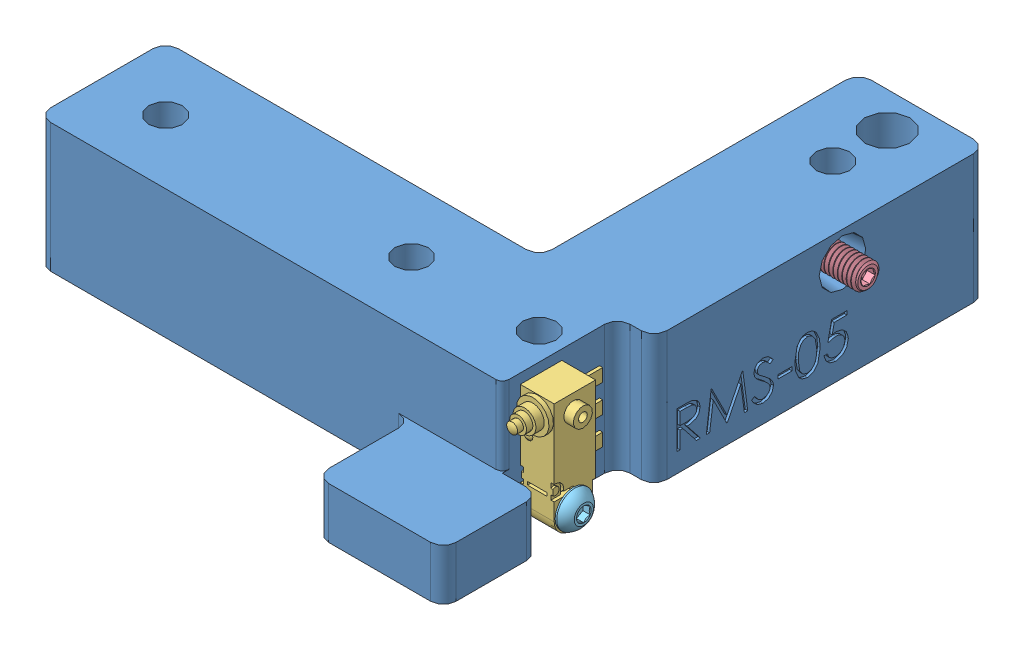
SolidWorks assembly tall_motor_corner_plate_spacer_assembly, configuration Default. Lengths in mm.
Overall size (83.2 23.2 85).
6 component instances, 5 part files, 17 mates.
Components (placement in the parent):
- tall_motor_corner_plate_spacer_with_insert-1: tall_motor_corner_plate_spacer_with_insert [Default] at (354.071 392.0105 -198.139) x (0 0 -1) z (0 1 0) size (85 78.5 23.2)
  - motor_corner_bracket_spacer-1: motor_corner_bracket_spacer [Right Motor Corner Bracket Spacer] at (-213.4548 157 -10) x (0 -1 0) z (-1 0 0) size (78.5 23.2 85)
  - m4_heat_set_insert_long_94180A353-1: m4_heat_set_insert_long_94180A353 [94180A353] at (-165.9548 20 -4.5) x (0.989318 0 -0.145772) z (0.145772 0 0.989318) size (6.35 8.38 6.35)
- D2HW_C201H-1: D2HW_C201H [Default] at (348.321 387.8105 9.5157) x (0 -1 0) z (-1 0 0) size (18.5 14.2 8.3)
- m4_set_screw_25mm_92605A124-1: m4_set_screw_25mm_92605A124 [92605A124] at (345.571 387.5105 -32.1843) x (0 -0.291374 0.956609) z (1 0 0) size (4.62 4.16 25.86)
- m3_8mm_buttonhead_screw_92095A181-1: m3_8mm_buttonhead_screw_92095A181 [92095A181] at (355.271 374.8105 9.5157) x (0 0 -1) z (1 0 0) size (5.7 5.7 9.95)
Mates (geometry in assembly coordinates):
- Coincident1594070787: coincident anti-aligned: plane of D2HW_C201H-1 through (353.621 390.4605 6.0157) normal (1 0 0); plane of m3_8mm_buttonhead_screw_92095A181-1 through (353.621 371.9605 9.5157) normal (-1 0 0)
- Parallel52: parallel aligned: plane of tall_motor_corner_plate_spacer_with_insert-1/motor_corner_bracket_spacer-1 through (354.071 392.0105 15.3157) normal (0 0 1); plane of D2HW_C201H-1 through (353.621 390.4605 12.5157) normal (0 0 1)
- Concentric754010294: concentric aligned: cylinder of tall_motor_corner_plate_spacer_with_insert-1/motor_corner_bracket_spacer-1 through (341.321 374.8105 9.5157) axis (1 0 0) radius 1.35; circle of m3_8mm_buttonhead_screw_92095A181-1
- Concentric754010295: concentric anti-aligned: cylinder of tall_motor_corner_plate_spacer_with_insert-1/motor_corner_bracket_spacer-1 through (275.571 387.5105 -32.1843) axis (1 0 0) radius 2.6; circle of m4_set_screw_25mm_92605A124-1
- Distance28: distance = 1 mm aligned: plane of m4_set_screw_25mm_92605A124-1 through (333.071 387.5105 -32.1843) normal (-1 0 0); plane of tall_motor_corner_plate_spacer_with_insert-1/motor_corner_bracket_spacer-1 through (334.071 392.0105 -4.6843) normal (-1 0 0)
- Coincident1594070887: coincident anti-aligned: plane of tall_motor_corner_plate_spacer_with_insert-1/motor_corner_bracket_spacer-1 through (348.321 382.0105 15.3157) normal (1 0 0); plane of SS0750300F070P1A-1 through (348.321 392.0105 8.8157) normal (-1 0 0)
- Concentric754010296: concentric anti-aligned: cylinder of tall_motor_corner_plate_spacer_with_insert-1/motor_corner_bracket_spacer-1 through (342.321 387.0605 9.5157) axis (1 0 0) radius 1.3; cylinder of SS0750300F070P1A-1 through (354.071 388.9105 10.3157) axis (-1 0 0) radius 1.1
- Concentric754010297: concentric anti-aligned: cylinder of tall_motor_corner_plate_spacer_with_insert-1/motor_corner_bracket_spacer-1 through (342.321 379.0605 9.5157) axis (1 0 0) radius 1.3; cylinder of SS0750300F070P1A-1 through (354.071 382.4105 10.3157) axis (-1 0 0) radius 1.1
- Coincident1594070891: coincident aligned: plane of tall_motor_corner_plate_spacer_with_insert-1/motor_corner_bracket_spacer-1 through (354.071 392.0105 15.3157) normal (0 0 1); plane of SS0750300F070P1A-2 through (354.071 392.0105 15.3157) normal (0 0 1)
- Coincident1594070892: coincident aligned: plane of tall_motor_corner_plate_spacer_with_insert-1/motor_corner_bracket_spacer-1 through (354.071 392.0105 15.3157) normal (0 1 0); plane of SS0750300F070P1A-2 through (354.071 392.0105 8.8157) normal (0 1 0)
- Coincident1594070894: coincident aligned: plane of tall_motor_corner_plate_spacer_with_insert-1/motor_corner_bracket_spacer-1 through (354.071 392.0105 -54.6843) normal (1 0 0); plane of D2HW_BL201H-1 through (354.071 389.7105 12.5157) normal (1 0 0)
- Concentric754010298: concentric aligned: circle of tall_motor_corner_plate_spacer_with_insert-1/motor_corner_bracket_spacer-1; cylinder of D2HW_BL201H-1 through (340.6597 387.0605 9.5157) axis (1 0 0) radius 1.1
- Concentric754010299: concentric aligned: cylinder of tall_motor_corner_plate_spacer_with_insert-1/motor_corner_bracket_spacer-1 through (342.321 379.0605 9.5157) axis (1 0 0) radius 1.3; cylinder of D2HW_BL201H-1 through (340.6597 379.0605 9.5157) axis (1 0 0) radius 1.1
- Coincident1594070910: coincident anti-aligned: plane of tall_motor_corner_plate_spacer_with_insert-1/motor_corner_bracket_spacer-1 through (348.321 382.0105 15.3157) normal (1 0 0); plane of D2HW_C201H-1 through (348.321 390.4605 6.0157) normal (-1 0 0)
- Concentric754010300: concentric aligned: cylinder of tall_motor_corner_plate_spacer_with_insert-1/motor_corner_bracket_spacer-1 through (341.321 387.8105 9.5157) axis (1 0 0) radius 1.5; cylinder of D2HW_C201H-1 through (346.821 387.8105 9.5157) axis (1 0 0) radius 1.5
- Coincident1594070911: coincident anti-aligned: plane of D2HW_C201H-1 through (353.621 390.4605 6.0157) normal (1 0 0); plane of m3_8mm_buttonhead_screw_92095A181-1 through (353.621 371.9605 9.5157) normal (-1 0 0)
- Concentric754010308: concentric aligned: cylinder of tall_motor_corner_plate_spacer_with_insert-1/motor_corner_bracket_spacer-1 through (341.321 374.8105 9.5157) axis (1 0 0) radius 1.35; circle of m3_8mm_buttonhead_screw_92095A181-1
